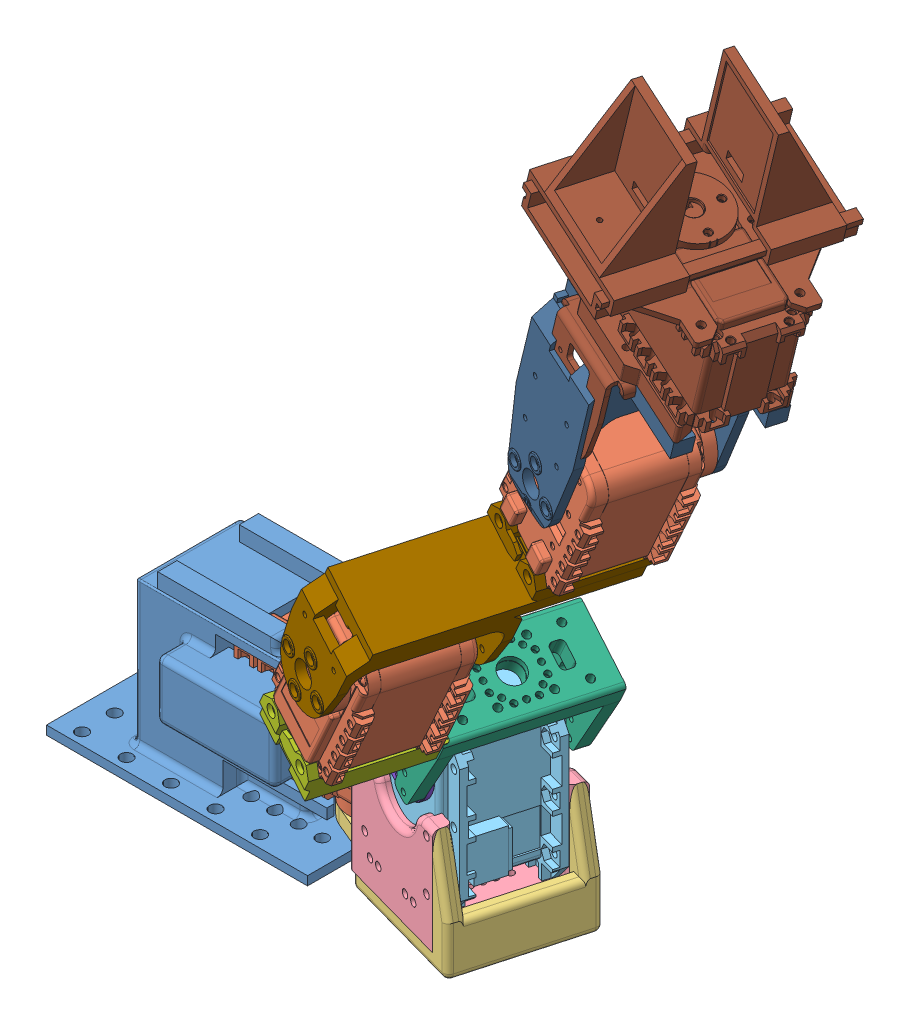
SolidWorks assembly RobotSerial, configuration Predeterminado. Lengths in mm.
Overall size (287.07 319.84 121.16).
16 component instances, 11 part files, 27 mates.
Components (placement in the parent):
- Base_serial.step-1: Base_serial.step [Predeterminado] at (6 -15.2495 88) x (1 0 0) z (0 1 0) size (88 55 56.5)
- AX-12A.step-1: AX-12A.step [Predeterminado] at (42 4.2505 88) x (0 0 -1) z (0 -1 0) size (32 50 40.05)
- Componentefinal.step-1: Componentefinal.step [Predeterminado] at (104.7297 -61.6763 93.0424) x (0 1 0) z (0.963133 0 0.269026) size (58.01 43.01 81.1)
  - BrackettDefinitivo.step-1: BrackettDefinitivo.step [Predeterminado] at (112.4984 -53.1349 -53.5955) size (58.01 43.01 81.1)
    - FP04-F2.step-1: FP04-F2.step [Predeterminado] at (-46.5715 65.1543 -8.178) size (58.01 43.01 81.1)
  - FR07-S101.step-1: FR07-S101.step [Predeterminado] at (48.6058 12.0195 -20.7736) x (0 0 -1) z (0 -1 0) size (40.9 35.6 43.01)
- MX-28T_R-03.step-1: MX-28T_R-03.step [Predeterminado] at (85.5893 28.7295 99.2171) x (-0.963133 0 -0.269026) z (0.269026 0 -0.963133) size (35.6 50.63 41.85)
- nuevosComponentes.step-1: nuevosComponentes.step [Predeterminado] at (72.9023 38.3428 126.575) x (-0.84209 0.485344 -0.235216) z (0.269026 0 -0.963133) size (26 41.51 88.04)
  - FR07-H101.step-1: FR07-H101.step [Predeterminado] at (-8.9144 -6.0467 30.4624) x (0 0 -1) z (1 0 0) size (50 34.5 26)
  - FP04-F3.step-1: FP04-F3.step [Predeterminado] at (-8.9144 23.9533 -13.5376) size (25.01 14.03 40.05)
- HN07-i101.stp-1: HN07-i101.stp [Predeterminado] at (80.2626 28.7295 118.2871) x (0.46745 0.874324 0.13057) z (0.84209 -0.485344 0.235216) size (22 3.05 22)
- AX-12A.step-2: AX-12A.step [Predeterminado] at (107.3632 91.2436 150.2565) x (0.84209 -0.485344 0.235216) z (-0.269026 0 0.963133) size (32 50 40.05)
- Interfas_3.step-1: Interfas_3.step [Predeterminado] at (120.9202 102.2723 117.2753) x (0.269026 0 -0.963133) z (0.46745 0.874324 0.13057) size (86.4 25 49)
- AX-12A.step-3: AX-12A.step [Predeterminado] at (151.8865 152.8834 118.047) x (-0.84209 0.485344 -0.235216) z (0.269026 0 -0.963133) size (32 50 40.05)
- Interfas_4.step-1: Interfas_4.step [Predeterminado] at (154.0769 173.4679 131.4537) x (-0.269026 0 0.963133) z (0.293378 0.952478 0.081947) size (49 54 69.04)
- Gripper_re.step-1: Gripper_re.step [Predeterminado] at (160.3197 215.1089 120.8004) x (-0.917363 0.304608 -0.256242) z (0.293378 0.952478 0.081947) size (60.37 71.61 119.85)
Mates (geometry in assembly coordinates):
- Concéntrica1: concentric aligned: cylinder of Base_serial.step-1 through (35.5 21.7505 101.5) axis (0 1 0) radius 1.25; cylinder of AX-12A.step-1 through (35.5 17.6505 101.5) axis (0 1 0) radius 1.1
- Coincidente1: coincident anti-aligned: plane of Base_serial.step-1 through (20.5 20.2505 105.501) normal (0 -1 0); plane of AX-12A.step-1 through (4.599 20.2505 88) normal (0 1 0)
- Concéntrica2: concentric anti-aligned: cylinder of Base_serial.step-1 through (35.5 21.7505 74.5) axis (0 1 0) radius 1.25; cylinder of AX-12A.step-1 through (35.5 18.4255 74.5) axis (0 -1 0) radius 1.1
- Concéntrica3: concentric anti-aligned: circle of AX-12A.step-1; cylinder of Componentefinal.step-1/BrackettDefinitivo.step-1/FP04-F2.step-1 through (42 26.7505 88) axis (0 1 0) radius 4
- Coincidente2: coincident anti-aligned: plane of AX-12A.step-1 through (41.9821 -16.7495 99.4161) normal (0 -1 0); plane of Componentefinal.step-1/BrackettDefinitivo.step-1/FP04-F2.step-1 through (61.0299 -16.7495 93.3155) normal (0 1 0)
- Coincidente5: coincident anti-aligned: plane of nuevosComponentes.step-1/FR07-H101.step-1 through (79.0893 26.5349 117.9594) normal (0.269026 0 -0.963133); plane of HN07-i101.stp-1 through (80.2626 28.7295 118.2871) normal (-0.269026 0 0.963133)
- Concéntrica9: concentric anti-aligned: cylinder of nuevosComponentes.step-1/FR07-H101.step-1 through (83.8004 35.7241 120.0541) axis (0.269026 0 -0.963133) radius 1; circle of HN07-i101.stp-1
- Concéntrica10: concentric anti-aligned: cylinder of nuevosComponentes.step-1/FP04-F3.step-1 through (92.752 55.8852 163.6184) axis (0.269026 0 -0.963133) radius 1.05; cylinder of AX-12A.step-2 through (93.2632 55.8852 161.7884) axis (-0.269026 0 0.963133) radius 1.1
- Concéntrica11: concentric aligned: cylinder of nuevosComponentes.step-1/FP04-F3.step-1 through (88.3179 63.6507 127.4936) axis (0.269026 0 -0.963133) radius 1.05; cylinder of AX-12A.step-2 through (87.4032 63.6507 130.7683) axis (0.269026 0 -0.963133) radius 1.1
- Coincidente6: coincident anti-aligned: plane of nuevosComponentes.step-1/FP04-F3.step-1 through (87.3968 62.3305 128.067) normal (-0.269026 0 0.963133); plane of AX-12A.step-2 through (94.1845 58.5431 129.963) normal (0.269026 0 -0.963133)
- Concéntrica13: concentric anti-aligned: circle of AX-12A.step-2; cylinder of Interfas_3.step-1 through (101.3101 91.2436 171.927) axis (0.269026 0 -0.963133) radius 4
- Coincidente7: coincident anti-aligned: plane of AX-12A.step-2 through (92.0919 96.7687 167.7947) normal (-0.269026 0 0.963133); plane of Interfas_3.step-1 through (110.9497 108.5188 173.0622) normal (0.269026 0 -0.963133)
- Concéntrica15: concentric anti-aligned: cylinder of Interfas_3.step-1 through (123.802 125.2905 127.6454) axis (-0.269026 0 0.963133) radius 1.05; cylinder of AX-12A.step-3 through (124.5082 125.2905 125.1172) axis (0.269026 0 -0.963133) radius 1.1
- Coincidente8: coincident anti-aligned: plane of Interfas_3.step-1 through (123.3156 123.9782 126.6789) normal (0.269026 0 -0.963133); plane of AX-12A.step-3 through (130.099 120.1829 128.5737) normal (-0.269026 0 0.963133)
- Concéntrica16: concentric aligned: cylinder of Interfas_3.step-1 through (146.3147 117.525 99.0476) axis (-0.269026 0 0.963133) radius 1.05; cylinder of AX-12A.step-3 through (145.4 117.525 102.3222) axis (-0.269026 0 0.963133) radius 1.1
- Concéntrica17: concentric anti-aligned: circle of AX-12A.step-3; cylinder of Interfas_4.step-1 through (157.9396 152.8834 96.3765) axis (-0.269026 0 0.963133) radius 4
- Coincidente9: coincident anti-aligned: plane of AX-12A.step-3 through (167.1411 147.3271 100.5042) normal (0.269026 0 -0.963133); plane of Interfas_4.step-1 through (170.9606 196.4673 101.571) normal (-0.269026 0 0.963133)
- Concéntrica19: concentric anti-aligned: cylinder of Interfas_4.step-1 through (173.0678 203.5944 123.9635) axis (0.293378 0.952478 0.081947) radius 5.75; cylinder of Gripper_re.step-1 through (176.0309 213.2144 124.7911) axis (-0.293378 -0.952478 -0.081947) radius 2.15
- Concéntrica20: concentric anti-aligned: cylinder of Interfas_4.step-1 through (204.6792 194.3039 118.7765) axis (0.293378 0.952478 0.081947) radius 1.25; cylinder of Gripper_re.step-1 through (206.4395 200.0187 119.2682) axis (-0.293378 -0.952478 -0.081947) radius 1.05
- Coincidente10: coincident anti-aligned: plane of Interfas_4.step-1 through (184.6742 204.3196 110.5919) normal (0.293378 0.952478 0.081947); plane of Gripper_re.step-1 through (198.4791 199.1995 120.6797) normal (-0.293378 -0.952478 -0.081947)
- Concéntrica21: concentric aligned: cylinder of Componentefinal.step-1/FR07-S101.step-1 through (97.7648 -7.0705 87.2236) axis (-0.269026 0 0.963133) radius 1.3; cylinder of MX-28T_R-03.step-1 through (97.4751 -7.0705 88.2608) axis (-0.269026 0 0.963133) radius 1.35
- Concéntrica23: concentric anti-aligned: circle of AX-12A.step-1; cylinder of Componentefinal.step-1/BrackettDefinitivo.step-1/FP04-F2.step-1 through (42 -18.2495 88) axis (0 1 0) radius 4
- Coincidente11: coincident anti-aligned: plane of Componentefinal.step-1/FR07-S101.step-1 through (74.2146 -4.4705 80.4657) normal (-0.269026 0 0.963133); plane of MX-28T_R-03.step-1 through (89.6247 -9.8715 84.7701) normal (0.269026 0 -0.963133)
- Coincidente14: coincident anti-aligned: plane of MX-28T_R-03.step-1 through (74.8218 28.7295 113.6006) normal (-0.269026 0 0.963133); plane of HN07-i101.stp-1 through (81.0831 28.7295 115.3496) normal (0.269026 0 -0.963133)
- Concéntrica24: concentric anti-aligned: circle of MX-28T_R-03.step-1; cylinder of HN07-i101.stp-1 through (80.2216 28.7295 118.434) axis (0.269026 0 -0.963133) radius 5
- Concéntrica26: concentric aligned: cylinder of Componentefinal.step-1/FR07-S101.step-1 through (81.3915 -7.0705 82.6501) axis (-0.269026 0 0.963133) radius 1.3; cylinder of MX-28T_R-03.step-1 through (81.1018 -7.0705 83.6873) axis (-0.269026 0 0.963133) radius 1.35
- Concéntrica27: concentric anti-aligned: circle of MX-28T_R-03.step-1; circle of nuevosComponentes.step-1/FR07-H101.step-1
